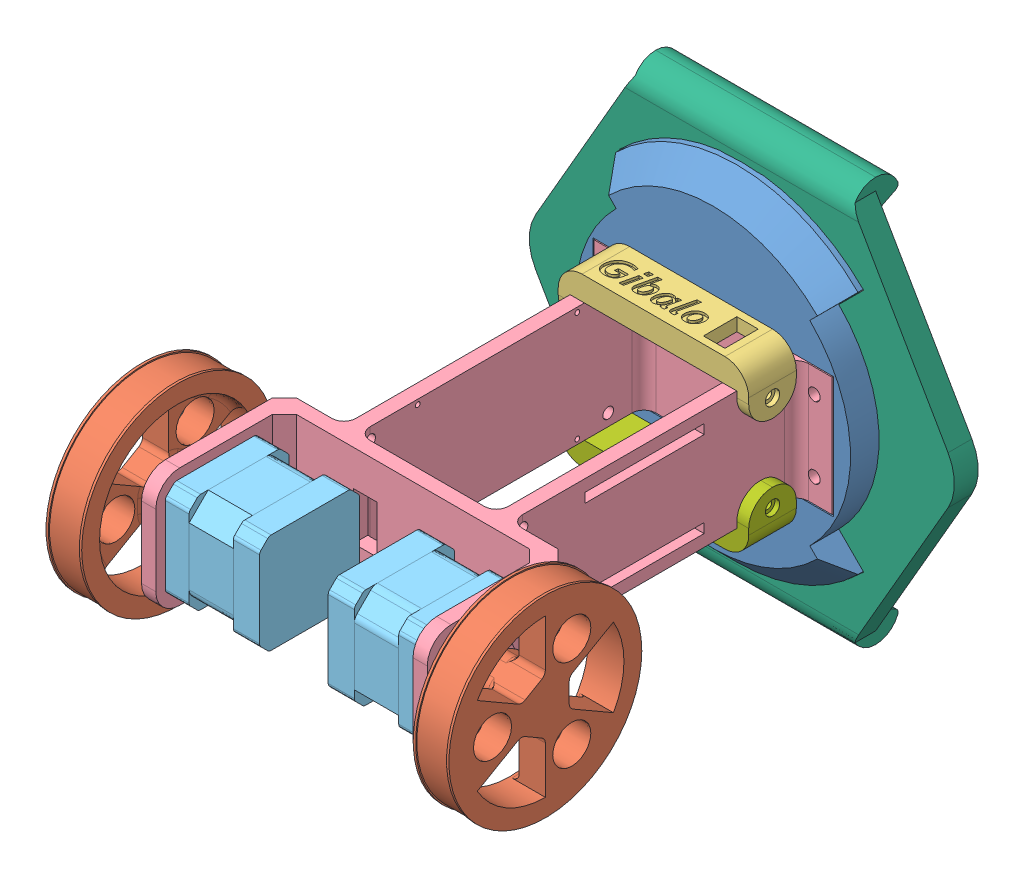
SolidWorks assembly GibaloV2.3, configuration Default. Lengths in mm.
Overall size (178.56 170 226.93).
9 component instances, 7 part files, 21 mates.
Components (placement in the parent):
- top_acc_plain-1: top_acc_plain [Default] at (-254.7675 22.1227 243.873) x (1 0 0) z (0 1 0) size (115.5 21 144.5)
- Wheel4-1: Wheel4 [Default] at (-339.3675 22.1227 398.873) x (0 -1 0) z (0 0 1) size (81 20 81)
- Wheel4-2: Wheel4 [Default] at (-170.1675 22.1227 398.873) x (0 1 0) z (0 0 1) size (81 20 81)
- bluetooth_mount-1: bluetooth_mount [Default] at (-255.7427 52.4323 268.873) x (1 0 0) z (0 1 0) size (80 20 22.5)
- Framev2-1: Framev2 [Default] at (-254.7675 -2.8773 398.873) size (120 50 185)
- nema17-1: nema17 [Default] at (-210.7675 22.1227 398.873) x (0 -1 0) z (0 0 1) size (42 64.2 42.5)
- nema17-2: nema17 [Default] at (-298.7675 22.1227 398.873) x (0 1 0) z (0 0 1) size (42 64.2 42.5)
- top_plain-1: top_plain [Default] at (-254.6613 22.0166 231.873) x (1 0 0) z (0 1 0) size (178.56 19.43 170)
- labmehsus-1: labmehsus [Default] at (-253.7922 -8.1869 268.873) x (-1 0 0) z (0 -1 0) size (80 20 22.5)
Mates (geometry in assembly coordinates):
- Concentric1: concentric anti-aligned: circle of Framev2-1; circle of nema17-2
- Parallel1: parallel anti-aligned: plane of Framev2-1 through (-308.7675 47.1227 369.873) normal (0 0 1); plane of nema17-2 through (-298.7675 22.1227 377.373) normal (0 0 -1)
- Concentric3: concentric aligned: cylinder of Framev2-1 through (-158.7675 22.1227 398.873) axis (-1 0 0) radius 12; cylinder of nema17-1 through (-176.1675 22.1227 398.873) axis (-1 0 0) radius 2.5
- Coincident2: coincident anti-aligned: plane of Framev2-1 through (-308.7675 47.1227 369.873) normal (1 0 0); plane of nema17-2 through (-308.7675 22.1227 398.873) normal (-1 0 0)
- Coincident3: coincident anti-aligned: plane of Framev2-1 through (-200.7675 47.1227 369.873) normal (-1 0 0); plane of nema17-1 through (-200.7675 22.1227 398.873) normal (1 0 0)
- Parallel2: parallel anti-aligned: plane of Framev2-1 through (-308.7675 47.1227 369.873) normal (0 0 1); plane of nema17-1 through (-210.7675 22.1227 377.373) normal (0 0 -1)
- Concentric4: concentric aligned: circle of Wheel4-2; circle of nema17-1
- Coincident5: coincident anti-aligned: plane of Wheel4-2 through (-176.1675 22.1227 398.873) normal (-1 0 0); plane of nema17-1 through (-176.1675 22.1227 398.873) normal (1 0 0)
- Concentric5: concentric aligned: cylinder of Wheel4-1 through (-333.3675 22.1227 398.873) axis (1 0 0) radius 2.6; circle of nema17-2
- Coincident6: coincident anti-aligned: plane of Wheel4-1 through (-333.3675 22.1227 398.873) normal (1 0 0); circle of nema17-2
- Coincident7: coincident anti-aligned: plane of top_acc_plain-1 through (-254.7675 22.1227 238.873) normal (0 0 1); plane of Framev2-1 through (-254.7675 -2.8773 238.873) normal (0 0 -1)
- Concentric6: concentric anti-aligned: circle of top_acc_plain-1; circle of Framev2-1
- Concentric7: concentric anti-aligned: cylinder of top_acc_plain-1 through (-254.7675 -19.8773 222.873) axis (0 0 1) radius 9.75; cylinder of top_plain-1 through (-254.7675 -19.8773 375.873) axis (0 0 -1) radius 10
- Coincident8: coincident anti-aligned: plane of top_acc_plain-1 through (-254.7675 22.1227 231.873) normal (0 0 -1); plane of top_plain-1 through (-254.6613 22.0166 231.873) normal (0 0 1)
- Parallel3: parallel anti-aligned: cylinder of top_acc_plain-1 through (-297.2675 37.1227 195.873) axis (0 0 1) radius 2; cylinder of top_plain-1 through (-297.1613 37.0166 242.873) axis (0 0 -1) radius 2
- Coincident9: coincident anti-aligned: plane of bluetooth_mount-1 through (-255.7427 47.1227 248.873) normal (0 -1 0); plane of Framev2-1 through (-254.7675 47.1227 398.873) normal (0 1 0)
- Coincident10: coincident anti-aligned: plane of bluetooth_mount-1 through (-289.7675 52.4323 248.873) normal (1 0 0); plane of Framev2-1 through (-289.7675 -2.8773 243.873) normal (-1 0 0)
- Concentric9: concentric aligned: cylinder of bluetooth_mount-1 through (-292.7675 42.1227 258.873) axis (-1 0 0) radius 3; cylinder of Framev2-1 through (-214.7675 42.1227 258.873) axis (-1 0 0) radius 2.25
- Coincident11: coincident anti-aligned: plane of Framev2-1 through (-254.7675 -2.8773 398.873) normal (0 -1 0); plane of labmehsus-1 through (-253.7922 -2.8773 248.873) normal (0 1 0)
- Coincident12: coincident anti-aligned: plane of Framev2-1 through (-289.7675 -2.8773 243.873) normal (-1 0 0); plane of labmehsus-1 through (-289.7675 -8.1869 248.873) normal (1 0 0)
- Concentric10: concentric aligned: cylinder of Framev2-1 through (-214.7675 2.1227 258.873) axis (-1 0 0) radius 2.25; cylinder of labmehsus-1 through (-200.7675 2.1227 258.873) axis (-1 0 0) radius 1.6
